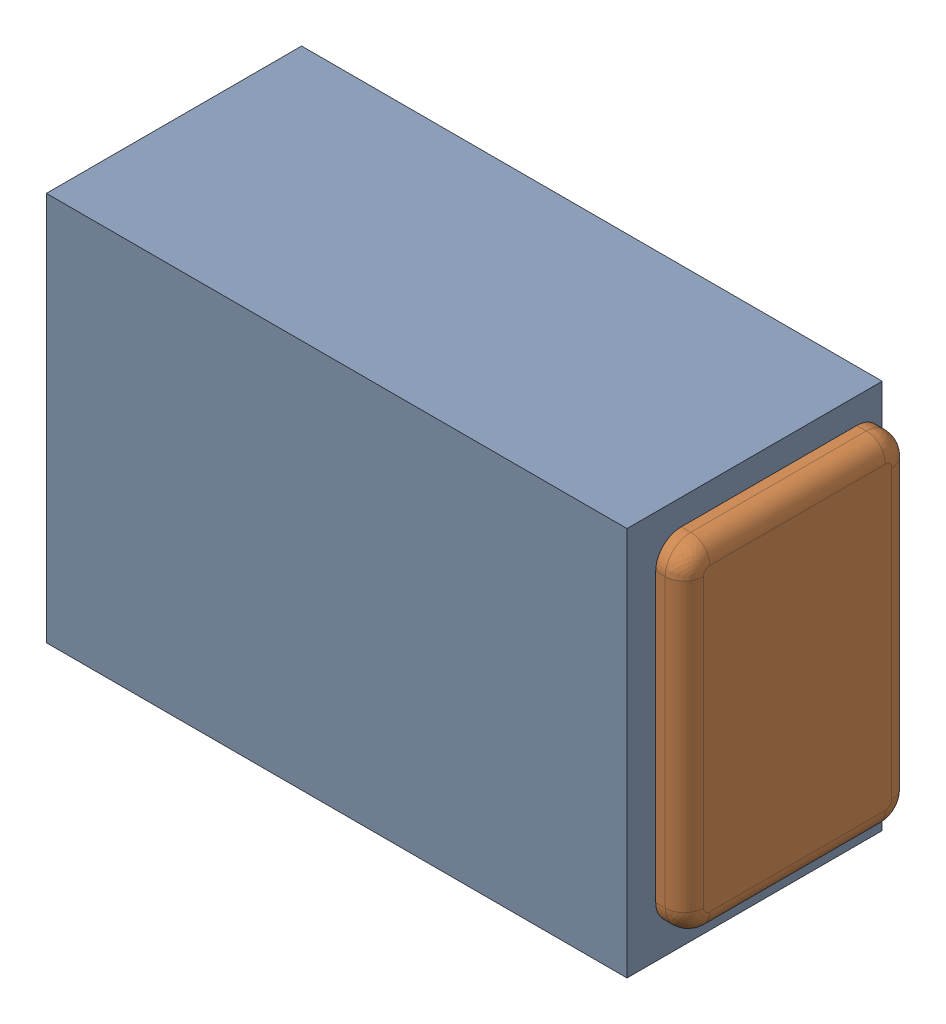
SolidWorks assembly C5, configuration Default. Lengths in mm.
Overall size (1 0.61 0.4).
3 component instances, 2 part files, 0 mates.
Components (placement in the parent):
- 1088880352-1: 1088880352 [Default] at (13.1 40 0) size (0.91 0.61 0.4)
  - Extruded-28-1: Extruded-28 [Default] at origin size (0.91 0.61 0.4)
- C0402-1: C0402 [Default] at (13.0999 39.9999 0) x (-1 0 0) z (0 1 0) size (1 0.36 0.54)
